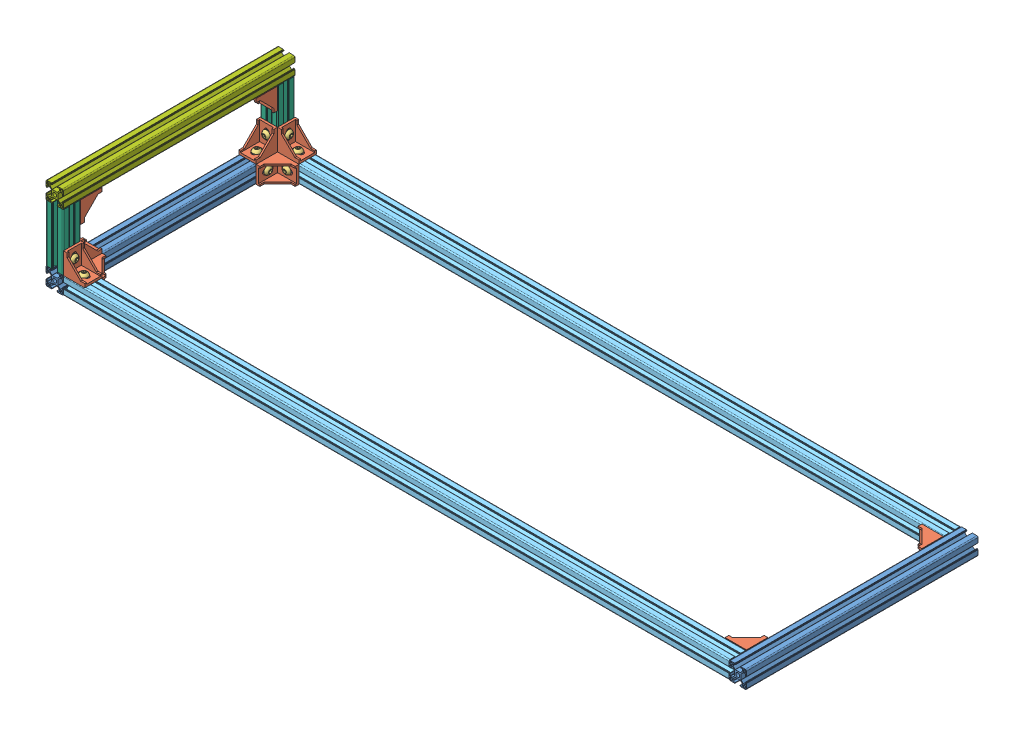
SolidWorks assembly 床板架, configuration 默认. Lengths in mm.
Overall size (1210 158.5 400).
67 component instances, 7 part files, 46 mates.
Components (placement in the parent):
- 3030_400mm-1: 3030_400mm [默认] at (-440.4529 129.8491 -251.8118) size (30 30 400)
- 3030_400mm-2: 3030_400mm [默认] at (739.5471 129.8491 -251.8118) x (0 1 0) z (0 0 1) size (30 30 400)
- 角码+螺栓-1: 角码+螺栓 [默认] at (712.9305 166.8491 -205.3258) x (1 0 0) z (0 -1 0) size (47 47 30)
  - 3030角码-1: 3030角码 [默认] at (-4.7227 -3.6958 22) size (37 37 30)
  - hexagon socket button head screws gb-1: hexagon socket button head screws gb [GB_SOCKET_TYPE7 M8X14-S] at (3.2166 3.743 36.75) x (1 0 0) z (0 0.018323 0.999832) size (18.4 14 14)
  - square nuts--product grade c gb-1: square nuts--product grade c gb [GB_SPECIAL_TYPE12 M8-C] at (19.9166 3.743 36.75) x (0 0.707107 -0.707107) z (1 0 0) size (18.38 18.38 6.5)
  - hexagon socket button head screws gb-2: hexagon socket button head screws gb [GB_SOCKET_TYPE7 M8X14-S] at (-9.1015 -8.086 36.75) x (0 -1 0) z (-0.830458 0 -0.557081) size (18.4 14 14)
  - square nuts--product grade c gb-2: square nuts--product grade c gb [GB_SPECIAL_TYPE12 M8-C] at (-9.1015 -24.786 36.75) x (0.707107 0 -0.707107) z (0 -1 0) size (18.38 18.38 6.5)
- 角码+螺栓-2: 角码+螺栓 [默认] at (-408.9669 166.8491 -210.1952) x (0 0 -1) z (0 -1 0) size (47 47 30)
  - 3030角码-1: 3030角码 [默认] at (-4.7227 -3.6958 22) size (37 37 30)
  - hexagon socket button head screws gb-1: hexagon socket button head screws gb [GB_SOCKET_TYPE7 M8X14-S] at (3.2166 3.743 36.75) x (1 0 0) z (0 0.018323 0.999832) size (18.4 14 14)
  - square nuts--product grade c gb-1: square nuts--product grade c gb [GB_SPECIAL_TYPE12 M8-C] at (19.9166 3.743 36.75) x (0 0.707107 -0.707107) z (1 0 0) size (18.38 18.38 6.5)
  - hexagon socket button head screws gb-2: hexagon socket button head screws gb [GB_SOCKET_TYPE7 M8X14-S] at (-9.1015 -8.086 36.75) x (0 -1 0) z (-0.830458 0 -0.557081) size (18.4 14 14)
  - square nuts--product grade c gb-2: square nuts--product grade c gb [GB_SPECIAL_TYPE12 M8-C] at (-9.1015 -24.786 36.75) x (0.707107 0 -0.707107) z (0 -1 0) size (18.38 18.38 6.5)
- 角码+螺栓-3: 角码+螺栓 [默认] at (712.9305 92.8491 101.7022) x (1 0 0) z (0 1 0) size (47 47 30)
  - 3030角码-1: 3030角码 [默认] at (-4.7227 -3.6958 22) size (37 37 30)
  - hexagon socket button head screws gb-1: hexagon socket button head screws gb [GB_SOCKET_TYPE7 M8X14-S] at (3.2166 3.743 36.75) x (1 0 0) z (0 0.018323 0.999832) size (18.4 14 14)
  - square nuts--product grade c gb-1: square nuts--product grade c gb [GB_SPECIAL_TYPE12 M8-C] at (19.9166 3.743 36.75) x (0 0.707107 -0.707107) z (1 0 0) size (18.38 18.38 6.5)
  - hexagon socket button head screws gb-2: hexagon socket button head screws gb [GB_SOCKET_TYPE7 M8X14-S] at (-9.1015 -8.086 36.75) x (0 -1 0) z (-0.830458 0 -0.557081) size (18.4 14 14)
  - square nuts--product grade c gb-2: square nuts--product grade c gb [GB_SPECIAL_TYPE12 M8-C] at (-9.1015 -24.786 36.75) x (0.707107 0 -0.707107) z (0 -1 0) size (18.38 18.38 6.5)
- 角码+螺栓-4: 角码+螺栓 [默认] at (-413.8363 166.8491 101.7022) x (-1 0 0) z (0 -1 0) size (47 47 30)
  - 3030角码-1: 3030角码 [默认] at (-4.7227 -3.6958 22) size (37 37 30)
  - hexagon socket button head screws gb-1: hexagon socket button head screws gb [GB_SOCKET_TYPE7 M8X14-S] at (3.2166 3.743 36.75) x (1 0 0) z (0 0.018323 0.999832) size (18.4 14 14)
  - square nuts--product grade c gb-1: square nuts--product grade c gb [GB_SPECIAL_TYPE12 M8-C] at (19.9166 3.743 36.75) x (0 0.707107 -0.707107) z (1 0 0) size (18.38 18.38 6.5)
  - hexagon socket button head screws gb-2: hexagon socket button head screws gb [GB_SOCKET_TYPE7 M8X14-S] at (-9.1015 -8.086 36.75) x (0 -1 0) z (-0.830458 0 -0.557081) size (18.4 14 14)
  - square nuts--product grade c gb-2: square nuts--product grade c gb [GB_SPECIAL_TYPE12 M8-C] at (-9.1015 -24.786 36.75) x (0.707107 0 -0.707107) z (0 -1 0) size (18.38 18.38 6.5)
- 3030_1100mm-3: 3030_1100mm [默认] at (724.5471 129.8491 -236.8118) x (0 -1 0) z (-1 0 0) size (30 30 1150)
- 3030_1100mm-4: 3030_1100mm [默认] at (724.5471 129.8491 133.1882) x (0 1 0) z (-1 0 0) size (30 30 1150)
- 3030_10mm_框架1-1: 3030_10mm_框架1 [默认] at (-440.4529 243.3491 133.1882) x (1 0 0) z (0 -1 0) size (30 30 98.5)
- 3030_10mm_框架1-3: 3030_10mm_框架1 [默认] at (-440.4529 243.3491 -236.8118) x (1 0 0) z (0 -1 0) size (30 30 98.5)
- 3030_40mm_框架2-2: 3030_40mm_框架2 [默认] at (-440.4529 258.3491 -251.8118) size (30 30 400)
- 角码+螺栓-5: 角码+螺栓 [默认] at (-477.4529 161.3351 -210.1952) x (0 0 -1) z (1 0 0) size (47 47 30)
  - 3030角码-1: 3030角码 [默认] at (-4.7227 -3.6958 22) size (37 37 30)
  - hexagon socket button head screws gb-1: hexagon socket button head screws gb [GB_SOCKET_TYPE7 M8X14-S] at (3.2166 3.743 36.75) x (1 0 0) z (0 0.018323 0.999832) size (18.4 14 14)
  - square nuts--product grade c gb-1: square nuts--product grade c gb [GB_SPECIAL_TYPE12 M8-C] at (19.9166 3.743 36.75) x (0 0.707107 -0.707107) z (1 0 0) size (18.38 18.38 6.5)
  - hexagon socket button head screws gb-2: hexagon socket button head screws gb [GB_SOCKET_TYPE7 M8X14-S] at (-9.1015 -8.086 36.75) x (0 -1 0) z (-0.830458 0 -0.557081) size (18.4 14 14)
  - square nuts--product grade c gb-2: square nuts--product grade c gb [GB_SPECIAL_TYPE12 M8-C] at (-9.1015 -24.786 36.75) x (0.707107 0 -0.707107) z (0 -1 0) size (18.38 18.38 6.5)
- 角码+螺栓-6: 角码+螺栓 [默认] at (-477.4529 226.8632 106.5716) x (0 0 1) z (1 0 0) size (47 47 30)
  - 3030角码-1: 3030角码 [默认] at (-4.7227 -3.6958 22) size (37 37 30)
  - hexagon socket button head screws gb-1: hexagon socket button head screws gb [GB_SOCKET_TYPE7 M8X14-S] at (3.2166 3.743 36.75) x (1 0 0) z (0 0.018323 0.999832) size (18.4 14 14)
  - square nuts--product grade c gb-1: square nuts--product grade c gb [GB_SPECIAL_TYPE12 M8-C] at (19.9166 3.743 36.75) x (0 0.707107 -0.707107) z (1 0 0) size (18.38 18.38 6.5)
  - hexagon socket button head screws gb-2: hexagon socket button head screws gb [GB_SOCKET_TYPE7 M8X14-S] at (-9.1015 -8.086 36.75) x (0 -1 0) z (-0.830458 0 -0.557081) size (18.4 14 14)
  - square nuts--product grade c gb-2: square nuts--product grade c gb [GB_SPECIAL_TYPE12 M8-C] at (-9.1015 -24.786 36.75) x (0.707107 0 -0.707107) z (0 -1 0) size (18.38 18.38 6.5)
- 角码+螺栓-7: 角码+螺栓 [默认] at (-477.4529 231.7325 -205.3258) x (0 1 0) z (1 0 0) size (47 47 30)
  - 3030角码-1: 3030角码 [默认] at (-4.7227 -3.6958 22) size (37 37 30)
  - hexagon socket button head screws gb-1: hexagon socket button head screws gb [GB_SOCKET_TYPE7 M8X14-S] at (3.2166 3.743 36.75) x (1 0 0) z (0 0.018323 0.999832) size (18.4 14 14)
  - square nuts--product grade c gb-1: square nuts--product grade c gb [GB_SPECIAL_TYPE12 M8-C] at (19.9166 3.743 36.75) x (0 0.707107 -0.707107) z (1 0 0) size (18.38 18.38 6.5)
  - hexagon socket button head screws gb-2: hexagon socket button head screws gb [GB_SOCKET_TYPE7 M8X14-S] at (-9.1015 -8.086 36.75) x (0 -1 0) z (-0.830458 0 -0.557081) size (18.4 14 14)
  - square nuts--product grade c gb-2: square nuts--product grade c gb [GB_SPECIAL_TYPE12 M8-C] at (-9.1015 -24.786 36.75) x (0.707107 0 -0.707107) z (0 -1 0) size (18.38 18.38 6.5)
- 角码+螺栓-8: 角码+螺栓 [默认] at (-477.4529 156.4658 101.7022) x (0 -1 0) z (1 0 0) size (47 47 30)
  - 3030角码-1: 3030角码 [默认] at (-4.7227 -3.6958 22) size (37 37 30)
  - hexagon socket button head screws gb-1: hexagon socket button head screws gb [GB_SOCKET_TYPE7 M8X14-S] at (3.2166 3.743 36.75) x (1 0 0) z (0 0.018323 0.999832) size (18.4 14 14)
  - square nuts--product grade c gb-1: square nuts--product grade c gb [GB_SPECIAL_TYPE12 M8-C] at (19.9166 3.743 36.75) x (0 0.707107 -0.707107) z (1 0 0) size (18.38 18.38 6.5)
  - hexagon socket button head screws gb-2: hexagon socket button head screws gb [GB_SOCKET_TYPE7 M8X14-S] at (-9.1015 -8.086 36.75) x (0 -1 0) z (-0.830458 0 -0.557081) size (18.4 14 14)
  - square nuts--product grade c gb-2: square nuts--product grade c gb [GB_SPECIAL_TYPE12 M8-C] at (-9.1015 -24.786 36.75) x (0.707107 0 -0.707107) z (0 -1 0) size (18.38 18.38 6.5)
- 角码+螺栓-13: 角码+螺栓 [默认] at (-413.8363 161.3351 170.1882) x (-1 0 0) z (0 0 -1) size (47 47 30)
  - 3030角码-1: 3030角码 [默认] at (-4.7227 -3.6958 22) size (37 37 30)
  - hexagon socket button head screws gb-1: hexagon socket button head screws gb [GB_SOCKET_TYPE7 M8X14-S] at (3.2166 3.743 36.75) x (1 0 0) z (0 0.018323 0.999832) size (18.4 14 14)
  - square nuts--product grade c gb-1: square nuts--product grade c gb [GB_SPECIAL_TYPE12 M8-C] at (19.9166 3.743 36.75) x (0 0.707107 -0.707107) z (1 0 0) size (18.38 18.38 6.5)
  - hexagon socket button head screws gb-2: hexagon socket button head screws gb [GB_SOCKET_TYPE7 M8X14-S] at (-9.1015 -8.086 36.75) x (0 -1 0) z (-0.830458 0 -0.557081) size (18.4 14 14)
  - square nuts--product grade c gb-2: square nuts--product grade c gb [GB_SPECIAL_TYPE12 M8-C] at (-9.1015 -24.786 36.75) x (0.707107 0 -0.707107) z (0 -1 0) size (18.38 18.38 6.5)
- 角码+螺栓-14: 角码+螺栓 [默认] at (-408.9669 156.4658 -273.8118) x (0 -1 0) z (0 0 1) size (47 47 30)
  - 3030角码-1: 3030角码 [默认] at (-4.7227 -3.6958 22) size (37 37 30)
  - hexagon socket button head screws gb-1: hexagon socket button head screws gb [GB_SOCKET_TYPE7 M8X14-S] at (3.2166 3.743 36.75) x (1 0 0) z (0 0.018323 0.999832) size (18.4 14 14)
  - square nuts--product grade c gb-1: square nuts--product grade c gb [GB_SPECIAL_TYPE12 M8-C] at (19.9166 3.743 36.75) x (0 0.707107 -0.707107) z (1 0 0) size (18.38 18.38 6.5)
  - hexagon socket button head screws gb-2: hexagon socket button head screws gb [GB_SOCKET_TYPE7 M8X14-S] at (-9.1015 -8.086 36.75) x (0 -1 0) z (-0.830458 0 -0.557081) size (18.4 14 14)
  - square nuts--product grade c gb-2: square nuts--product grade c gb [GB_SPECIAL_TYPE12 M8-C] at (-9.1015 -24.786 36.75) x (0.707107 0 -0.707107) z (0 -1 0) size (18.38 18.38 6.5)
Mates (geometry in assembly coordinates):
- 重合12: coincident: plane of 3030_400mm-1 through (-425.4529 134.9491 148.1882) normal (1 0 0); plane of 角码+螺栓-2/3030角码-1 through (-425.4529 114.8491 -184.8118) normal (-1 0 0)
- 重合22: coincident: plane of 3030_400mm-1 through (-425.4529 134.9491 148.1882) normal (1 0 0); plane of 角码+螺栓-4/3030角码-1 through (-425.4529 114.8491 81.1882) normal (-1 0 0)
- 重合23: coincident: plane of 3030_400mm-1 through (-435.3529 144.8491 148.1882) normal (0 1 0); plane of 角码+螺栓-4/3030角码-1 through (-409.1136 144.8491 105.398) normal (0 1 0)
- 重合25: coincident: plane of 角码+螺栓-1/3030角码-1 through (687.5471 114.8491 -221.8118) normal (0 0 -1); plane of 3030_1100mm-3 through (-425.4529 124.7491 -221.8118) normal (0 0 1)
- 重合27: coincident: plane of 角码+螺栓-1/3030角码-1 through (708.2078 144.8491 -209.0216) normal (0 1 0); plane of 3030_1100mm-3 through (-425.4529 144.8491 -231.7118) normal (0 1 0)
- 重合28: coincident: plane of 3030_1100mm-3 through (-425.4529 144.8491 -231.7118) normal (0 1 0); plane of 角码+螺栓-2/3030角码-1 through (-412.6627 144.8491 -205.4725) normal (0 1 0)
- 重合29: coincident: plane of 角码+螺栓-2/3030角码-1 through (-388.4529 114.8491 -221.8118) normal (0 0 -1); plane of 3030_1100mm-3 through (-425.4529 134.9491 -221.8118) normal (0 0 1)
- 重合30: coincident: plane of 3030_400mm-1 through (-425.4529 134.9491 148.1882) normal (1 0 0); plane of 3030_1100mm-4 through (-425.4529 129.8491 133.1882) normal (-1 0 0)
- 重合34: coincident: plane of 角码+螺栓-4/3030角码-1 through (-388.4529 114.8491 118.1882) normal (0 0 1); plane of 3030_1100mm-4 through (-425.4529 124.7491 118.1882) normal (0 0 -1)
- 重合35: coincident: plane of 3030_400mm-1 through (-435.3529 144.8491 148.1882) normal (0 1 0); plane of 3030_1100mm-4 through (-425.4529 144.8491 138.2882) normal (0 1 0)
- 重合36: coincident: plane of 3030_400mm-1 through (-425.4529 134.9491 148.1882) normal (1 0 0); plane of 3030_1100mm-3 through (-425.4529 129.8491 -236.8118) normal (-1 0 0)
- 重合37: coincident: plane of 3030_400mm-1 through (-440.4529 129.8491 -251.8118) normal (0 0 -1); plane of 3030_1100mm-3 through (-425.4529 134.9491 -251.8118) normal (0 0 -1)
- 重合39: coincident: plane of 角码+螺栓-3/3030角码-1 through (687.5471 144.8491 118.1882) normal (0 0 1); plane of 3030_1100mm-4 through (-425.4529 134.9491 118.1882) normal (0 0 -1)
- 重合40: coincident: plane of 3030_400mm-2 through (739.5471 129.8491 148.1882) normal (0 0 1); plane of 3030_1100mm-4 through (-425.4529 134.9491 148.1882) normal (0 0 1)
- 重合41: coincident: plane of 3030_400mm-2 through (739.5471 129.8491 -251.8118) normal (0 0 -1); plane of 3030_1100mm-3 through (-425.4529 134.9491 -251.8118) normal (0 0 -1)
- 重合42: coincident: plane of 3030_400mm-1 through (-435.3529 144.8491 148.1882) normal (0 1 0); plane of 3030_10mm_框架1-1 through (-440.4529 144.8491 133.1882) normal (0 -1 0)
- 重合43: coincident: plane of 3030_400mm-1 through (-455.4529 134.9491 148.1882) normal (-1 0 0); plane of 3030_10mm_框架1-1 through (-455.4529 144.8491 138.2882) normal (-1 0 0)
- 重合44: coincident: plane of 3030_400mm-1 through (-440.4529 129.8491 148.1882) normal (0 0 1); plane of 3030_10mm_框架1-1 through (-445.5529 144.8491 148.1882) normal (0 0 1)
- 重合45: coincident: plane of 3030_400mm-1 through (-435.3529 144.8491 148.1882) normal (0 1 0); plane of 3030_10mm_框架1-3 through (-440.4529 144.8491 -236.8118) normal (0 -1 0)
- 重合46: coincident: plane of 3030_400mm-1 through (-455.4529 134.9491 148.1882) normal (-1 0 0); plane of 3030_10mm_框架1-3 through (-455.4529 144.8491 -241.9118) normal (-1 0 0)
- 重合47: coincident: plane of 3030_400mm-1 through (-440.4529 129.8491 -251.8118) normal (0 0 -1); plane of 3030_10mm_框架1-3 through (-445.5529 144.8491 -251.8118) normal (0 0 -1)
- 重合48: coincident: plane of 3030_10mm_框架1-3 through (-435.3529 144.8491 -251.8118) normal (0 0 -1); plane of 3030_40mm_框架2-2 through (-440.4529 258.3491 -251.8118) normal (0 0 -1)
- 重合49: coincident: plane of 3030_10mm_框架1-3 through (-440.4529 243.3491 -236.8118) normal (0 1 0); plane of 3030_40mm_框架2-2 through (-445.5529 243.3491 148.1882) normal (0 -1 0)
- 重合50: coincident: plane of 3030_10mm_框架1-1 through (-455.4529 144.8491 128.0882) normal (-1 0 0); plane of 3030_40mm_框架2-2 through (-455.4529 253.2491 148.1882) normal (-1 0 0)
- 重合51: coincident: plane of 3030_40mm_框架2-2 through (-445.5529 243.3491 148.1882) normal (0 -1 0); plane of 角码+螺栓-6/3030角码-1 through (-425.4529 243.3491 81.1882) normal (0 1 0)
- 重合52: coincident: plane of 3030_10mm_框架1-1 through (-445.5529 144.8491 118.1882) normal (0 0 -1); plane of 角码+螺栓-6/3030角码-1 through (-425.4529 206.3491 118.1882) normal (0 0 1)
- 重合53: coincident: plane of 3030_40mm_框架2-2 through (-455.4529 253.2491 148.1882) normal (-1 0 0); plane of 角码+螺栓-6/3030角码-1 through (-455.4529 230.559 101.8489) normal (-1 0 0)
- 重合54: coincident: plane of 3030_10mm_框架1-3 through (-435.3529 144.8491 -221.8118) normal (0 0 1); plane of 角码+螺栓-5/3030角码-1 through (-425.4529 181.8491 -221.8118) normal (0 0 -1)
- 重合55: coincident: plane of 3030_400mm-1 through (-435.3529 144.8491 148.1882) normal (0 1 0); plane of 角码+螺栓-5/3030角码-1 through (-425.4529 144.8491 -184.8118) normal (0 -1 0)
- 重合56: coincident: plane of 3030_10mm_框架1-3 through (-455.4529 144.8491 -231.7118) normal (-1 0 0); plane of 角码+螺栓-5/3030角码-1 through (-455.4529 157.6393 -205.4725) normal (-1 0 0)
- 重合57: coincident: plane of 3030_10mm_框架1-3 through (-445.5529 144.8491 -221.8118) normal (0 0 1); plane of 角码+螺栓-7/3030角码-1 through (-425.4529 206.3491 -221.8118) normal (0 0 -1)
- 重合58: coincident: plane of 3030_40mm_框架2-2 through (-435.3529 243.3491 148.1882) normal (0 -1 0); plane of 角码+螺栓-7/3030角码-1 through (-425.4529 243.3491 -184.8118) normal (0 1 0)
- 重合59: coincident: plane of 3030_40mm_框架2-2 through (-425.4529 253.2491 148.1882) normal (1 0 0); plane of 角码+螺栓-7/3030角码-1 through (-425.4529 227.0099 -209.0216) normal (1 0 0)
- 重合60: coincident: plane of 3030_10mm_框架1-1 through (-445.5529 144.8491 118.1882) normal (0 0 -1); plane of 角码+螺栓-8/3030角码-1 through (-425.4529 181.8491 118.1882) normal (0 0 1)
- 重合61: coincident: plane of 3030_400mm-1 through (-435.3529 144.8491 148.1882) normal (0 1 0); plane of 角码+螺栓-8/3030角码-1 through (-425.4529 144.8491 81.1882) normal (0 -1 0)
- 重合62: coincident: plane of 3030_10mm_框架1-1 through (-425.4529 144.8491 128.0882) normal (1 0 0); plane of 角码+螺栓-8/3030角码-1 through (-425.4529 161.1884 105.398) normal (1 0 0)
- 重合82: coincident: plane of 3030_10mm_框架1-1 through (-435.3529 144.8491 148.1882) normal (0 0 1); plane of 角码+螺栓-13/3030角码-1 through (-409.1136 157.6393 148.1882) normal (0 0 1)
- 重合83: coincident: plane of 3030_1100mm-4 through (-425.4529 144.8491 138.2882) normal (0 1 0); plane of 角码+螺栓-13/3030角码-1 through (-388.4529 144.8491 118.1882) normal (0 -1 0)
- 重合84: coincident: plane of 3030_10mm_框架1-1 through (-425.4529 144.8491 138.2882) normal (1 0 0); plane of 角码+螺栓-13/3030角码-1 through (-425.4529 181.8491 118.1882) normal (-1 0 0)
- 重合85: coincident: plane of 3030_1100mm-3 through (-425.4529 144.8491 -241.9118) normal (0 1 0); plane of 角码+螺栓-14/3030角码-1 through (-388.4529 144.8491 -221.8118) normal (0 -1 0)
- 重合86: coincident: plane of 3030_10mm_框架1-3 through (-425.4529 144.8491 -241.9118) normal (1 0 0); plane of 角码+螺栓-14/3030角码-1 through (-425.4529 181.8491 -221.8118) normal (-1 0 0)
- 重合87: coincident: plane of 3030_10mm_框架1-3 through (-435.3529 144.8491 -251.8118) normal (0 0 -1); plane of 角码+螺栓-14/3030角码-1 through (-412.6627 161.1884 -251.8118) normal (0 0 -1)
- 重合88: coincident: plane of 3030_400mm-2 through (724.5471 124.7491 148.1882) normal (-1 0 0); plane of 角码+螺栓-3/3030角码-1 through (724.5471 144.8491 81.1882) normal (1 0 0)
- 重合89: coincident: plane of 角码+螺栓-3/3030角码-1 through (708.2078 144.8491 105.398) normal (0 1 0); plane of 3030_1100mm-4 through (-425.4529 144.8491 128.0882) normal (0 1 0)
- 重合90: coincident: plane of 3030_400mm-2 through (734.4471 144.8491 148.1882) normal (0 1 0); plane of 角码+螺栓-3/3030角码-1 through (708.2078 144.8491 105.398) normal (0 1 0)
- 重合91: coincident: plane of 3030_400mm-2 through (724.5471 134.9491 148.1882) normal (-1 0 0); plane of 3030_1100mm-4 through (724.5471 129.8491 133.1882) normal (1 0 0)
